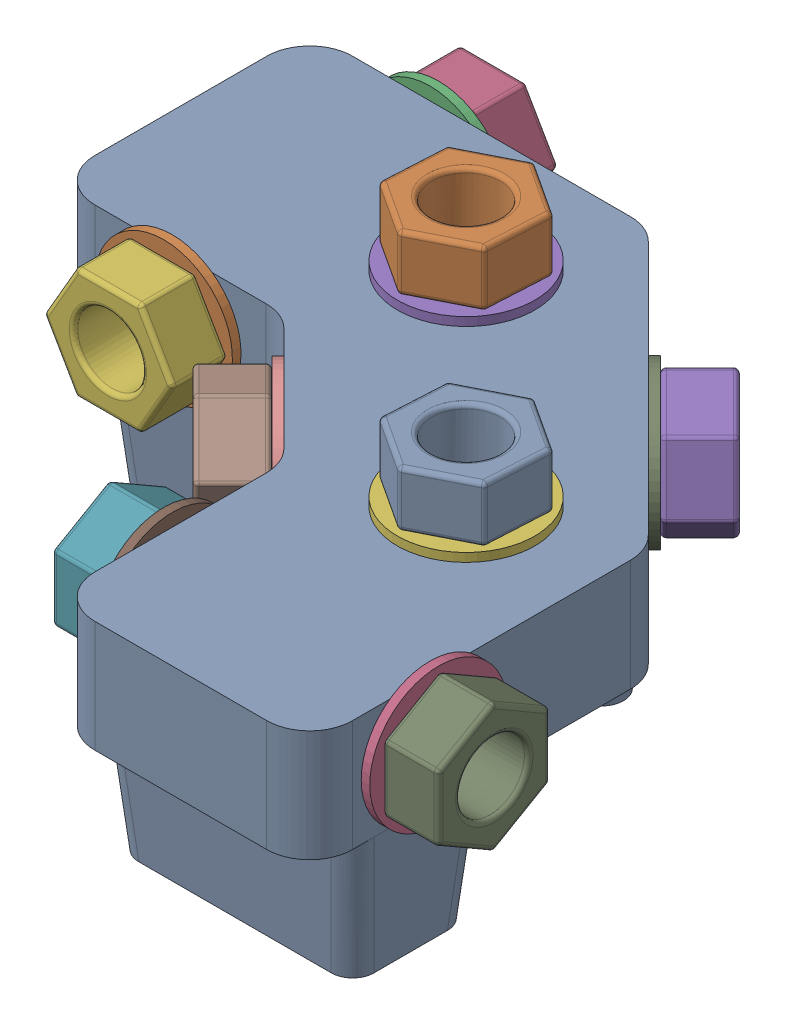
SolidWorks assembly Corner with Washers and Nuts, configuration Default. Lengths in mm.
Overall size (79.5 35.5 79.5).
21 component instances, 3 part files, 20 mates.
Components (placement in the parent):
- Corner (Lower)-1: Corner (Lower) [Default] at origin size (72 28 72)
- M8 Washer 16mm-1: M8 Washer 16mm [Default] at (-28 6.5 1) x (1 0 0) z (0 1 0) size (16 1 16)
- M8 Washer 16mm-2: M8 Washer 16mm [Default] at (-28 6.5 -30) x (1 0 0) z (0 1 0) size (16 1 16)
- M8 Washer 16mm-3: M8 Washer 16mm [Default] at (31 6.5 28) x (0 1 0) z (0 0 1) size (16 1 16)
- M8 Washer 16mm-4: M8 Washer 16mm [Default] at (-8.7868 14 -15) x (-0.837169 0 -0.546944) z (-0.546944 0 0.837169) size (16 1 16)
- M8 Washer 16mm-5: M8 Washer 16mm [Default] at (15 14 8.7868) x (-0.837169 0 -0.546944) z (-0.546944 0 0.837169) size (16 1 16)
- M8 Washer 16mm-6: M8 Washer 16mm [Default] at (-8.7868 0 -15) x (-0.837169 0 -0.546944) z (-0.546944 0 0.837169) size (16 1 16)
- M8 Washer 16mm-7: M8 Washer 16mm [Default] at (15 0 8.7868) x (-0.837169 0 -0.546944) z (-0.546944 0 0.837169) size (16 1 16)
- M8 Washer 16mm-8: M8 Washer 16mm [Default] at (14.4203 6.5 -14.4203) x (0.5 0.707107 0.5) z (0.5 -0.707107 0.5) size (16 1 16)
- M8 Washer 16mm-9: M8 Washer 16mm [Default] at (-8.2071 6.5 8.2071) x (0.5 -0.707107 0.5) z (0.5 0.707107 0.5) size (16 1 16)
- M8 Washer 16mm-10: M8 Washer 16mm [Default] at (-1 6.5 28) x (0 -1 0) z (0 0 1) size (16 1 16)
- M8 Nut-1: M8 Nut [Default] at (15 -7.5 8.7868) size (14.85 6.5 12.99)
- M8 Nut-2: M8 Nut [Default] at (15 20.5 8.7868) x (-0.837169 0 -0.546944) z (-0.546944 0 0.837169) size (14.85 6.5 12.99)
- M8 Nut-3: M8 Nut [Default] at (-8.7868 20.5 -15) x (-0.837169 0 -0.546944) z (-0.546944 0 0.837169) size (14.85 6.5 12.99)
- M8 Nut-4: M8 Nut [Default] at (-8.7868 -7.5 -15) size (14.85 6.5 12.99)
- M8 Nut-5: M8 Nut [Default] at (-28 6.5 -37.5) x (1 0 0) z (0 -1 0) size (14.85 6.5 12.99)
- M8 Nut-6: M8 Nut [Default] at (19.0165 6.5 -19.0165) x (0.5 0.707107 0.5) z (0.5 -0.707107 0.5) size (14.85 6.5 12.99)
- M8 Nut-7: M8 Nut [Default] at (-28 6.5 7.5) x (1 0 0) z (0 1 0) size (14.85 6.5 12.99)
- M8 Nut-8: M8 Nut [Default] at (-7.5 6.5 28) x (0 -1 0) z (0 0 1) size (14.85 6.5 12.99)
- M8 Nut-9: M8 Nut [Default] at (-12.8033 6.5 12.8033) x (0.5 -0.707107 0.5) z (0.5 0.707107 0.5) size (14.85 6.5 12.99)
- M8 Nut-10: M8 Nut [Default] at (37.5 6.5 28) x (0 1 0) z (0 0 1) size (14.85 6.5 12.99)
Mates (geometry in assembly coordinates):
- Coincident31: coincident anti-aligned: circle of Corner (Lower)-1; circle of M8 Washer 16mm-1
- Coincident32: coincident anti-aligned: circle of M8 Washer 16mm-4; circle of Corner (Lower)-1
- Coincident33: coincident anti-aligned: circle of Corner (Lower)-1; circle of M8 Washer 16mm-5
- Coincident34: coincident aligned: circle of M8 Washer 16mm-3; circle of Corner (Lower)-1
- Coincident35: coincident aligned: circle of Corner (Lower)-1; circle of M8 Washer 16mm-8
- Coincident36: coincident anti-aligned: circle of M8 Washer 16mm-7; circle of Corner (Lower)-1
- Coincident37: coincident anti-aligned: circle of M8 Washer 16mm-6; circle of Corner (Lower)-1
- Coincident38: coincident anti-aligned: circle of M8 Washer 16mm-10; circle of Corner (Lower)-1
- Coincident39: coincident anti-aligned: circle of Corner (Lower)-1; circle of M8 Washer 16mm-9
- Coincident40: coincident anti-aligned: circle of Corner (Lower)-1; circle of M8 Washer 16mm-2
- Coincident48: coincident anti-aligned: circle of M8 Washer 16mm-1; circle of M8 Nut-7
- Coincident45: coincident aligned: circle of M8 Washer 16mm-2; circle of M8 Nut-5
- Coincident43: coincident anti-aligned: circle of M8 Washer 16mm-3; circle of M8 Nut-10
- Coincident42: coincident anti-aligned: circle of M8 Washer 16mm-4; circle of M8 Nut-3
- Coincident41: coincident anti-aligned: circle of M8 Nut-2; circle of M8 Washer 16mm-5
- Coincident50: coincident aligned: circle of M8 Washer 16mm-6; circle of M8 Nut-4
- Coincident49: coincident aligned: circle of M8 Washer 16mm-7; circle of M8 Nut-1
- Coincident44: coincident anti-aligned: circle of M8 Washer 16mm-8; circle of M8 Nut-6
- Coincident46: coincident anti-aligned: circle of M8 Washer 16mm-9; circle of M8 Nut-9
- Coincident47: coincident anti-aligned: circle of M8 Washer 16mm-10; circle of M8 Nut-8
